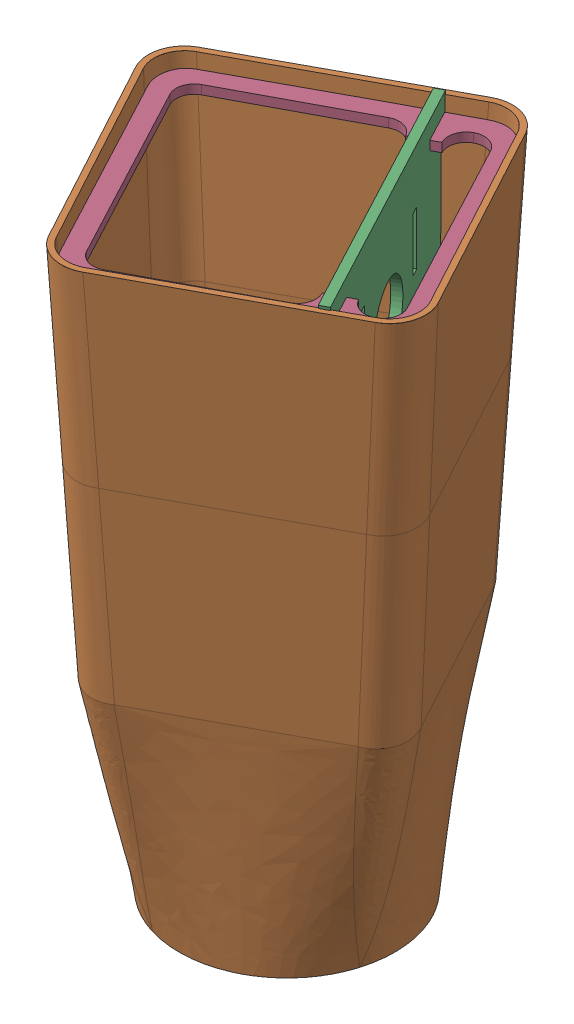
SolidWorks assembly nose_assembly, configuration Default. Lengths in mm.
Overall size (137.71 216.95 137.71).
5 component instances, 5 part files, 8 mates.
Components (placement in the parent):
- Nose_cone_firewall-1: Nose_cone_firewall [Default] at (-15.6874 5.2515 1.2946) size (72.39 6.35 72.39)
- NewNose-1: NewNose [Default] at (-16.3514 221.1261 2.0637) x (-0.475967 0 -0.879463) z (0 -1 0) size (101.6 101.6 215.89)
- bat_plate-1: bat_plate [Default] at (6.8321 158.6897 -10.45) x (0 1 0) z (0.469155 0 0.883116) size (177.8 3.17 98.36)
- bat_rib-2: bat_rib [Default] at (-16.2356 212.7715 1.6217) x (-0.469155 0 -0.883116) z (0 1 0) size (96.52 96.52 3.17)
- bat_rib_front-1: bat_rib_front [Default] at (-16.9134 69.7897 1.1579) x (0.469155 0 0.883116) z (0 -1 0) size (82.04 82.04 2.54)
Mates (geometry in assembly coordinates):
- Tangent4: tangent: circle of Nose_cone_firewall-1; curve of NewNose-1
- Parallel2: parallel: plane of Nose_cone_firewall-1 through (-15.6874 5.2515 1.2946) normal (0 -1 0); plane of NewNose-1 through (-16.3514 5.2515 2.0637) normal (0 -1 0)
- Coincident19: coincident anti-aligned: plane of bat_plate-1 through (-17.1994 158.6897 -48.9184) normal (-0.469155 0 -0.883116); plane of bat_rib-2 through (-14.3956 215.9465 -50.408) normal (0.469155 0 0.883116)
- Coincident20: coincident anti-aligned: plane of bat_plate-1 through (6.8321 158.6897 -10.45) normal (0.883116 0 -0.469155); plane of bat_rib-2 through (-14.3956 215.9465 -50.408) normal (-0.883116 0 0.469155)
- Coincident21: coincident anti-aligned: plane of bat_plate-1 through (4.0282 215.9465 -8.9604) normal (0 -1 0); plane of bat_rib-2 through (-16.2356 215.9465 1.6217) normal (0 1 0)
- Coincident23: coincident anti-aligned: plane of bat_plate-1 through (18.5067 158.6897 18.2932) normal (0.469155 0 0.883116); plane of bat_rib_front-1 through (-2.0177 67.2497 29.1969) normal (-0.469155 0 -0.883116)
- Coincident24: coincident anti-aligned: plane of bat_plate-1 through (4.0282 69.7897 -8.9604) normal (0 -1 0); plane of bat_rib_front-1 through (-16.9134 69.7897 1.1579) normal (0 1 0)
- Coincident25: coincident anti-aligned: plane of bat_plate-1 through (4.0282 158.6897 -8.9604) normal (-0.883116 0 0.469155); plane of bat_rib_front-1 through (3.6111 67.2497 -9.7457) normal (0.883116 0 -0.469155)
